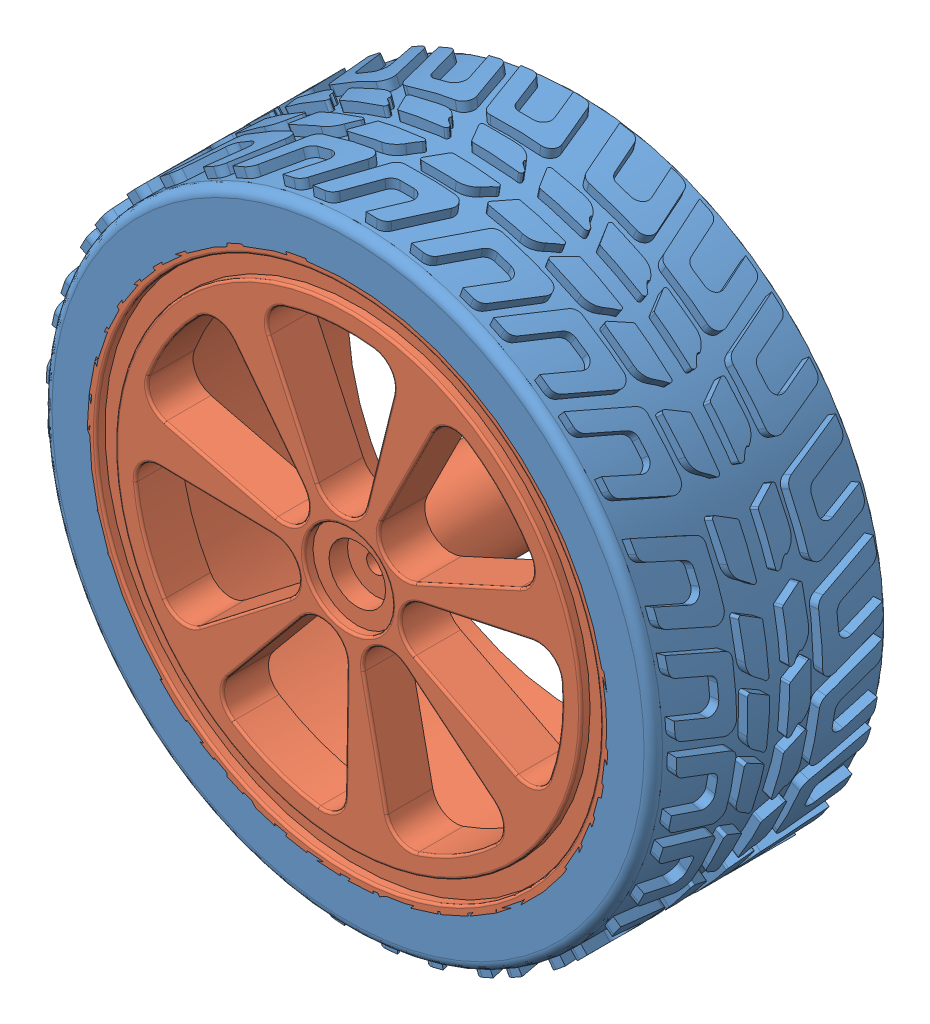
SolidWorks assembly Wheel Assemble, configuration 默认. Lengths in mm.
Overall size (68.01 68.01 25).
2 component instances, 2 part files, 2 mates.
Components (placement in the parent):
- Tire-1: Tire [默认] at origin size (68.01 68.01 24.89)
- WheelFrame-2: WheelFrame [默认] at (-797.8323 -276.5666 -0.108) size (56.38 56.38 25)
Mates (geometry in assembly coordinates):
- 同心1: concentric: cylinder of Tire-1 through (0 0 24.892) axis (0 0 -1) radius 27.94; cylinder of WheelFrame-2 through (0 0 24.892) axis (0 0 -1) radius 28.1902
- 重合1: coincident aligned: plane of Tire-1 through (0 0 24.892) normal (0 0 1); plane of WheelFrame-2 through (0 0 24.892) normal (0 0 1)
